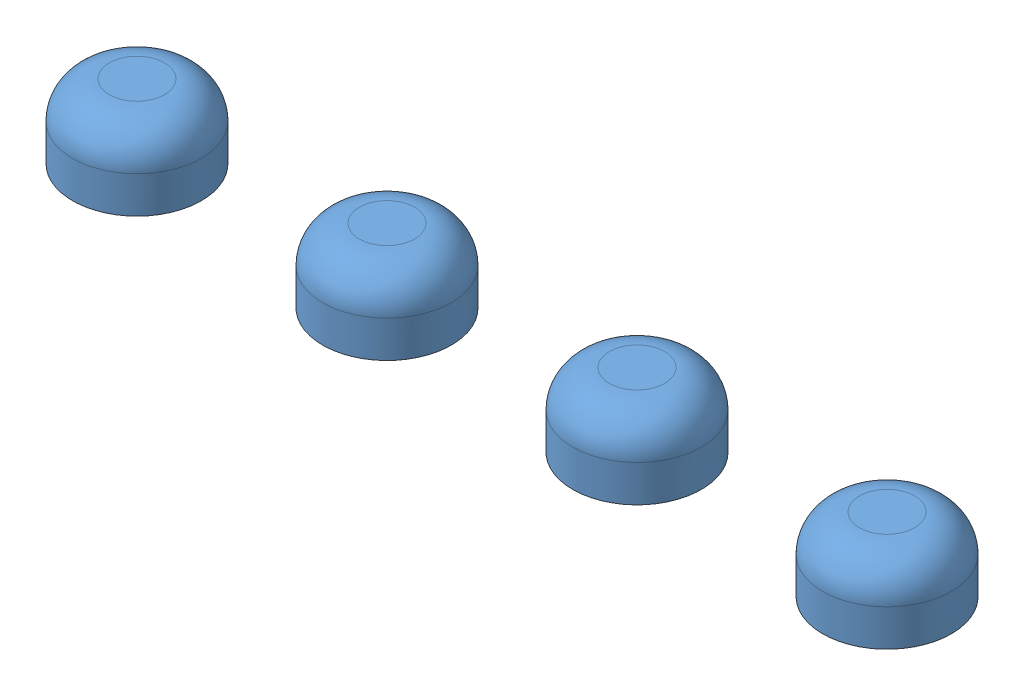
SolidWorks assembly ButtonTops, configuration Default. Lengths in mm.
Overall size (25.28 2 4.93).
4 component instances, 1 part files, 13 mates.
Components (placement in the parent):
- ButtonTop-1: ButtonTop [Default] at (1.75 0 0) x (0.547252 0 0.836968) z (-0.836968 0 0.547252) size (3.5 2 3.5)
- ButtonTop-2: ButtonTop [Default] at (8.55 0 0) x (-0.633962 0 0.773364) z (-0.773364 0 -0.633962) size (3.5 2 3.5)
- ButtonTop-3: ButtonTop [Default] at (15.35 0 0) x (0.997167 0 -0.075213) z (0.075213 0 0.997167) size (3.5 2 3.5)
- ButtonTop-4: ButtonTop [Default] at (22.15 0 0) x (0.792761 0 -0.609532) z (0.609532 0 0.792761) size (3.5 2 3.5)
Mates (geometry in assembly coordinates):
- Coincident1: coincident anti-aligned: plane of assembly through (0 0 0) normal (0 1 0); plane of ButtonTop-3 through (15.35 0 0) normal (0 -1 0)
- Coincident6: coincident: plane of assembly through (0 0 0) normal (0 1 0); plane of assembly; plane of ButtonTop-1 through (1.75 0 0) normal (0 -1 0)
- Coincident7: coincident: plane of assembly through (0 0 0) normal (0 1 0); plane of assembly; plane of ButtonTop-4 through (22.15 0 0) normal (0 -1 0)
- Coincident8: coincident: plane of assembly through (0 0 0) normal (0 1 0); plane of assembly; plane of ButtonTop-2 through (8.55 0 0) normal (0 -1 0)
- Coincident9: coincident: plane of assembly through (0 0 0) normal (0 1 0); plane of assembly; plane of ButtonTop-3 through (15.35 0 0) normal (0 -1 0)
- Coincident10: coincident: point of assembly; line of assembly; point of ButtonTop-1
- Coincident11: coincident: point of assembly; line of assembly; point of ButtonTop-4
- Coincident12: coincident: point of assembly; line of assembly; point of ButtonTop-3
- Coincident13: coincident: point of assembly; line of assembly; point of ButtonTop-2
- Distance1: distance = 6.8 mm: point of ButtonTop-1; point of ButtonTop-2
- Distance2: distance = 6.8 mm: point of ButtonTop-2; point of ButtonTop-3
- Distance3: distance = 6.8 mm: point of ButtonTop-4; point of ButtonTop-3
- Tangent1: tangent anti-aligned: cylinder of ButtonTop-1 through (1.75 2 0) axis (0 -1 0) radius 1.75
